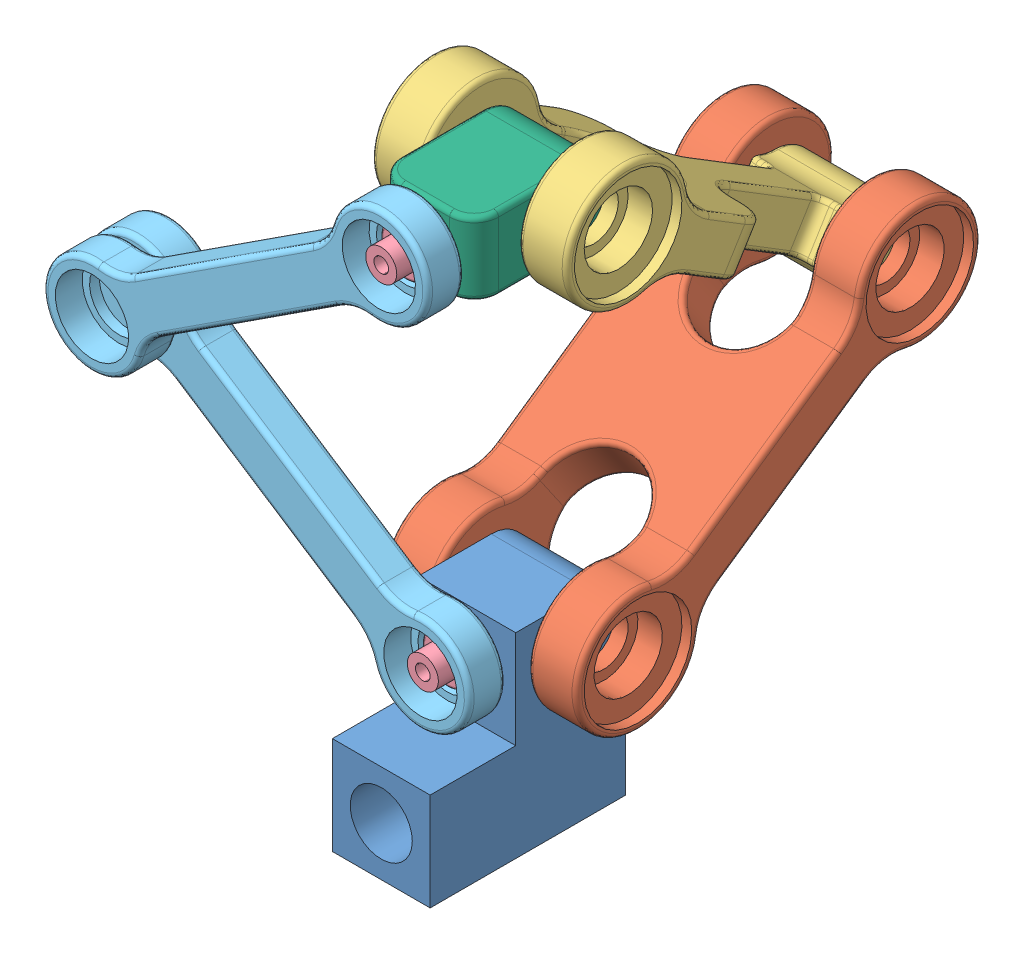
SolidWorks assembly Assem1, configuration Default. Lengths in mm.
Overall size (92.5 126.07 108.02).
8 component instances, 6 part files, 19 mates.
Components (placement in the parent):
- rotating base-1: rotating base [Default] at origin size (20 40 40)
- Link 1-1: Link 1 [Default] at (0 32.3609 -41.3192) x (0 -0.567454 0.823405) z (-1 0 0) size (95 25 40)
- Link 2-1: Link 2 [Default] at (0 70.5471 -40.3192) x (0 -0.523581 -0.851976) z (1 0 0) size (90 25 40)
- axle1-1: axle1 [Default] at (0 12.5 2.5) x (0 0 1) z (-1 0 0) size (19 10.35 10.35)
- link guide-1: link guide [Link 1 - Guide] at (-29.3335 31.5931 4.5) x (-0.838099 0.545517 0) z (0 0 1) size (90 20 7.5)
- link guide-2: link guide [link2 - guide] at (-29.3335 69.7793 13) x (0.838099 0.545517 0) z (0 0 1) size (90 20 7.5)
- link 3 a-1: link 3 a [Default] at (0 88.8724 -3.5) x (0 0 1) z (-1 0 0) size (29 15 20)
- axle1-2: axle1 [Default] at (0 88.8724 11) x (0 0 1) z (0 -1 0) size (19 10.35 10.35)
Mates (geometry in assembly coordinates):
- Concentric1: concentric anti-aligned: cylinder of rotating base-1 through (10 12.5 -12.5) axis (-1 0 0) radius 3.175; cylinder of Link 1-1 through (-20.001 12.5 -12.5) axis (1 0 0) radius 5
- Coincident1: coincident anti-aligned: plane of rotating base-1 through (10 20 -20) normal (1 0 0); plane of Link 1-1 through (10 -4.8857 -9.3006) normal (-1 0 0)
- Concentric2: concentric anti-aligned: cylinder of Link 1-1 through (-20.001 52.2218 -70.1383) axis (1 0 0) radius 5; cylinder of Link 2-1 through (20 52.2218 -70.1383) axis (-1 0 0) radius 3.175
- Coincident2: coincident anti-aligned: plane of Link 1-1 through (-10 49.0224 -87.5241) normal (1 0 0); plane of Link 2-1 through (-10 37.6453 -69.9834) normal (-1 0 0)
- Concentric3: concentric anti-aligned: cylinder of rotating base-1 through (0 12.5 -20.001) axis (0 0 1) radius 3.175; cylinder of axle1-1 through (0 12.5 -32.3244) axis (0 0 -1) radius 3.175
- Coincident3: coincident anti-aligned: plane of rotating base-1 through (-10 0 2.5) normal (0 0 1); plane of axle1-1 through (0 15.675 2.5) normal (0 0 -1)
- Concentric4: concentric anti-aligned: cylinder of axle1-1 through (0 12.5 -32.3244) axis (0 0 -1) radius 3.175; cylinder of link guide-1 through (0 12.5 4.5) axis (0 0 1) radius 6
- Coincident4: coincident aligned: circle of axle1-1; plane of link guide-1 through (-39.3972 56.0412 6.5) normal (0 0 1)
- Concentric5: concentric anti-aligned: cylinder of link guide-1 through (-58.667 50.6862 12) axis (0 0 -1) radius 3.175; cylinder of link guide-2 through (-58.667 50.6862 13) axis (0 0 1) radius 6
- Distance1: distance = 1 mm anti-aligned: plane of link guide-1 through (-39.3972 56.0412 12) normal (0 0 1); plane of link guide-2 through (-2.9043 69.0844 13) normal (0 0 -1)
- Concentric6: concentric aligned: cylinder of Link 2-1 through (20.001 88.8724 -10.5) axis (-1 0 0) radius 5; cylinder of link 3 a-1 through (10 88.8724 -10.5) axis (-1 0 0) radius 3.175
- Coincident6: coincident anti-aligned: plane of Link 2-1 through (-10 84.7675 6.6945) normal (1 0 0); plane of link 3 a-1 through (-10 96.3724 -18) normal (-1 0 0)
- Concentric10: concentric anti-aligned: cylinder of link 3 a-1 through (0 88.8724 -18.001) axis (0 0 1) radius 3.175; cylinder of axle1-2 through (0 88.8724 -23.8244) axis (0 0 -1) radius 3.175
- Coincident9: coincident anti-aligned: plane of link 3 a-1 through (10 96.3724 11) normal (0 0 1); plane of axle1-2 through (-3.175 88.8724 11) normal (0 0 -1)
- Coincident10: coincident aligned: plane of link guide-2 through (-2.9043 69.0844 15) normal (0 0 1); plane of axle1-2 through (-5.175 88.8724 15) normal (0 0 1)
- Concentric11: concentric anti-aligned: cylinder of link guide-2 through (0 88.8724 -8.2132) axis (0 0 1) radius 7.5; cylinder of axle1-2 through (0 88.8724 -23.8244) axis (0 0 -1) radius 3.175
- LimitAngle1: limit planar angle = 1.154013 rad anti-aligned: plane of link guide-1 through (-8.3594 23.907 12) normal (0.545517 0.838099 0); plane of link guide-2 through (-44.8524 53.7122 20.5) normal (0.545517 -0.838099 0)
- Coincident13: coincident aligned: plane of link 3 a-1 through (0 88.8724 -3.5) normal (-1 0 0); plane of axle1-2
- Coincident14: coincident anti-aligned: plane of rotating base-1 through (0 0 0) normal (1 0 0); plane of axle1-1 through (0 12.5 2.5) normal (-1 0 0)
